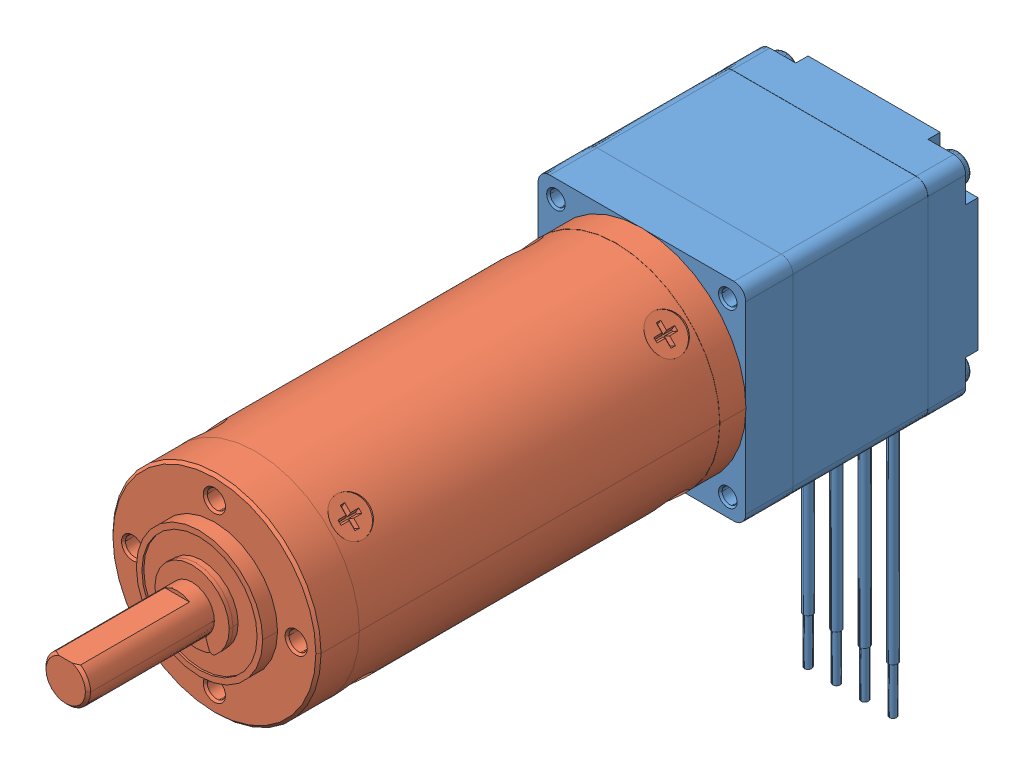
SolidWorks assembly J3ActualMotorMockUp, configuration Default. Lengths in mm.
Overall size (28 67.98 109).
3 component instances, 2 part files, 0 mates.
Components (placement in the parent):
- 11YPG1-R189.STEP-1: 11YPG1-R189.STEP [Default] at origin size (28 67.98 109)
  - 11Y Series_11Y102S-LW4.STEP-1: 11Y Series_11Y102S-LW4.STEP [Default] at origin size (27.94 67.95 51.31)
  - 11YPG Gearbox_11YPG-R189.STEP-1: 11YPG Gearbox_11YPG-R189.STEP [Default] at (0 0 57.5) size (28 28 77.5)
